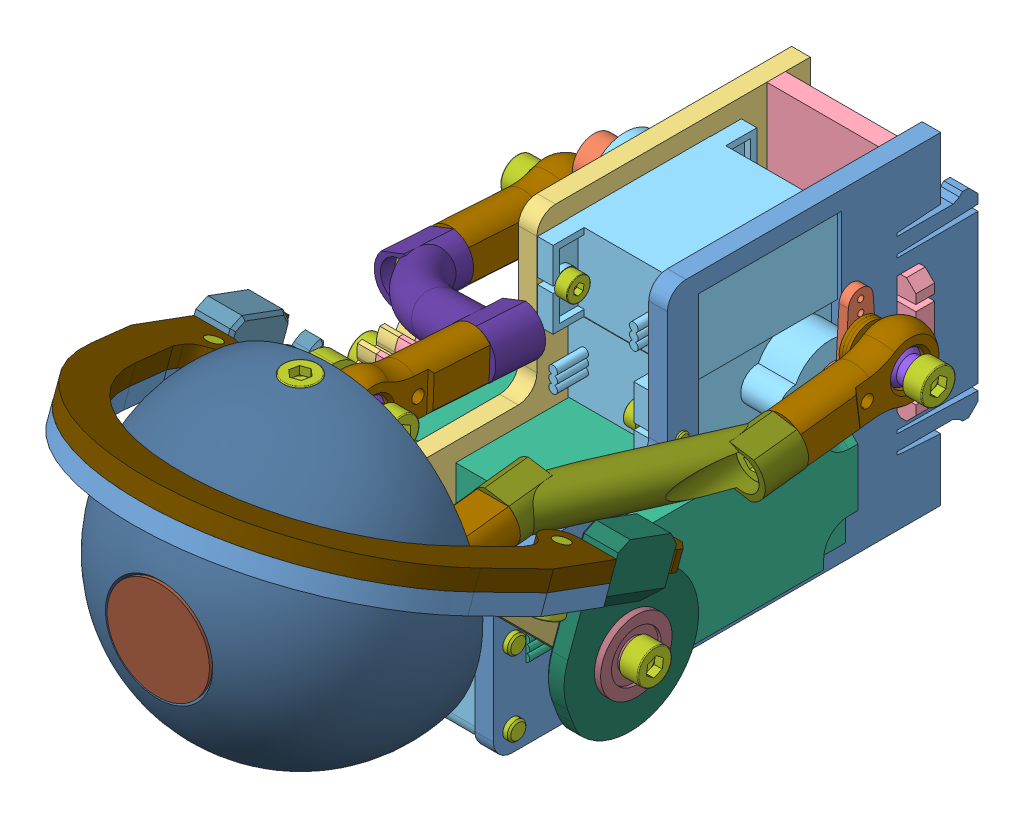
SolidWorks assembly eye, configuration Default. Lengths in mm.
Overall size (70 58.01 124.02).
83 component instances, 27 part files, 174 mates.
Components (placement in the parent):
- eye-frame-2-1: eye-frame-2 [Default] at origin size (3 52 78)
- eye-frame-4-1: eye-frame-4 [Default] at origin size (3 37 29)
- eye-frame-1-1: eye-frame-1 [Default] at origin size (3 52 78)
- eye-frame-3-1: eye-frame-3 [Default] at origin size (30 52 3)
- servo-micro-1: servo-micro [Default] at (11.5 42.75 27.5) x (0 0 1) z (0 -1 0) size (32.8 31.5 12.4)
- servo-micro-2: servo-micro [Default] at (-11.5 30.25 27.5) x (0 0 1) z (0 1 0) size (32.8 31.5 12.4)
- servo-standard-1: servo-standard [Default] at (14.9 13.5 36.5) x (0 0 -1) z (0 1 0) size (58.5 43.2 20.3)
- pivot-beam-1: pivot-beam [Default] at (0 33 91) x (1 0 0) z (0 0.999996 0.002896) size (13.6 17.5 43)
- balljoint-ball-1: balljoint-ball [Default] at (-27 34.2513 22.1498) x (0 -1 0) z (0 0 1) size (6 8 6)
- balljoint-ball-2: balljoint-ball [Default] at (27 38.7499 22.3456) x (0 -0.456904 -0.889516) z (0 0.889516 -0.456904) size (6 8 6)
- balljoint-ball-3: balljoint-ball [Default] at (-0.1 48.0274 81.5435) x (0 -0.381849 0.924225) z (0 -0.924225 -0.381849) size (6 8 6)
- balljoint-housing-1: balljoint-housing [Default] at (27 38.7499 22.3456) x (0.002874 -0.992667 -0.120847) z (-0.003489 -0.120857 0.992664) size (11 6 23.5)
- balljoint-housing-2: balljoint-housing [Default] at (-27 34.2513 22.1498) x (0.013011 -0.998189 0.05873) z (-0.003694 0.058687 0.99827) size (11 6 23.5)
- balljoint-housing-3: balljoint-housing [Default] at (-0.1 48.0274 81.5435) x (-0.020817 0.998056 -0.058751) z (0.003694 -0.058687 -0.99827) size (11 6 23.5)
- eye-shell-1: eye-shell [Default] at (0 33 91) x (0 0.999996 0.002896) z (0.999533 0.000089 -0.03056) size (50 27.56 50)
- iris-1: iris [Default] at (0.7238 32.9314 114.6743) x (-0.245832 0.969257 0.010323) z (-0.968831 -0.246032 0.028909) size (16 3 16)
- balljoint-ball-5: balljoint-ball [Default] at (12.9939 33.0012 90.6027) x (1 0 0) z (0 -0.002896 0.999996) size (6 8 6)
- balljoint-housing-4: balljoint-housing [Default] at (12.9939 33.0012 90.6027) x (-0.999969 -0.006611 -0.00432) z (0.003489 0.120857 -0.992664) size (11 6 23.5)
- eyelid-spacer-1: eyelid-spacer [Default] at (-12 23.5 69) x (0 1 0) z (0 0 1) size (8 16 7)
- eyelid-spacer-2: eyelid-spacer [Default] at (12 23.5 69) x (0 -1 0) z (0 0 1) size (8 16 7)
- bearing-f623-1: bearing-f623 [Default] at (-32 23.5 69) x (0 -1 0) z (0 0 1) size (11.5 4 11.5)
- bearing-f623-2: bearing-f623 [Default] at (32 23.5 69) x (0 -0.381849 0.924225) z (0 -0.924225 -0.381849) size (11.5 4 11.5)
- eyelid-gear-1: eyelid-gear [Default] at (-28 23.5 69) x (0 -0.716341 0.69775) z (-1 0 0) size (27.51 29.21 6)
- eyelid-idler-2: eyelid-idler [Default] at (28 23.5 69) x (0 -0.716341 0.69775) z (-1 0 0) size (25.22 26.99 6)
- lever-horizontal-1: lever-horizontal [Default] at (19.997 35.8755 56.4742) x (0.983361 -0.180711 -0.018545) z (-0.003489 -0.120857 0.992664) size (22 7.47 32.5)
- lever-vertical-1: lever-vertical [Default] at (-13.55 41.1394 51.8466) x (-0.93523 -0.353617 0.017328) z (0.003694 -0.058687 -0.99827) size (37 7.61 24)
- eyelid-2: eyelid [Default] at (0 41.9081 86.4801) x (-1 0 0) z (0 -0.345125 -0.938557) size (68 3 57.5)
- eyelid-lower-1: eyelid-lower [Default] at (0 41.9081 86.4801) x (1 0 0) z (0 -0.345125 -0.938557) size (68 3 44.5)
- servo-horn-micro-1-arm-1: servo-horn-micro-1-arm [Default] at (17 30.25 22.3) x (0 0.999986 0.005367) z (0 0.005367 -0.999986) size (19.5 4.5 7)
- servo-horn-micro-1-arm-2: servo-horn-micro-1-arm [Default] at (-17 42.75 22.3) x (0 -0.999844 -0.01767) z (0 0.01767 -0.999844) size (19.5 4.5 7)
- eyelid-servo-gear-lasered-a-1: eyelid-servo-gear-lasered-a [Default] at (-31.3 13.5 46.6) x (0 0 -1) z (1 0 0) size (26.64 26.59 3)
- eyelid-servo-gear-lasered-b-1: eyelid-servo-gear-lasered-b [Default] at (-28.3 13.5 46.6) x (0 0 -1) z (1 0 0) size (26.64 26.59 3)
- eye-frame-spacer-1: eye-frame-spacer [Default] at (-9 3.5 69) x (0 0 -1) z (0 -1 0) size (9 7.5 27.3)
- eye-frame-spacer-3: eye-frame-spacer [Default] at (9 3.5 69) x (0 0 1) z (0 -1 0) size (9 7.5 27.3)
- pan head cross recess screw_iso-2: pan head cross recess screw_iso [ISO 7045 - M2.5 x 4 - Z --- 4N] at (-22.6 42.75 22.3) size (6.05 5 5)
- socket head cap screw_iso-1: socket head cap screw_iso [ISO 4762 M2 x 6 --- 6N] at (-4.5 42.75 41.75) x (-1 0 0) z (0 -0.924225 -0.381849) size (8 3.8 3.8)
- socket head cap screw_iso-2: socket head cap screw_iso [ISO 4762 M2 x 6 --- 6N] at (-4.5 42.75 13.25) x (-1 0 0) z (0 -0.924225 -0.381849) size (8 3.8 3.8)
- socket head cap screw_iso-3: socket head cap screw_iso [ISO 4762 M2 x 6 --- 6N] at (4.5 30.25 41.75) x (1 0 0) z (0 0.924225 -0.381849) size (8 3.8 3.8)
- socket head cap screw_iso-4: socket head cap screw_iso [ISO 4762 M2 x 6 --- 6N] at (4.5 30.25 13.25) x (1 0 0) z (0 0.924225 -0.381849) size (8 3.8 3.8)
- socket head cap screw_iso-5: socket head cap screw_iso [ISO 4762 M3 x 6 --- 6N] at (-17.5 18.5 61) size (9 5.5 5.5)
- socket head cap screw_iso-6: socket head cap screw_iso [ISO 4762 M3 x 6 --- 6N] at (-17.5 8.5 61) size (9 5.5 5.5)
- socket head cap screw_iso-7: socket head cap screw_iso [ISO 4762 M3 x 6 --- 6N] at (-17.5 18.5 12) size (9 5.5 5.5)
- socket head cap screw_iso-8: socket head cap screw_iso [ISO 4762 M3 x 6 --- 6N] at (-17.5 8.5 12) size (9 5.5 5.5)
- hex nut style 1 gradeab_iso-1: hex nut style 1 gradeab_iso [Hexagon Nut ISO - 4032 - M3 - D - N] at (-3.7 23.5 69) x (0 0 1) z (-1 0 0) size (5.5 6.35 2.4)
- hex nut style 1 gradeab_iso-2: hex nut style 1 gradeab_iso [Hexagon Nut ISO - 4032 - M3 - D - N] at (3.7 23.5 69) x (0 0 1) z (1 0 0) size (5.5 6.35 2.4)
- hex nut style 1 gradeab_iso-3: hex nut style 1 gradeab_iso [Hexagon Nut ISO - 4032 - M3 - D - N] at (-6.4 33 91) x (0 0.86747 -0.49749) z (-1 0 0) size (5.5 6.35 2.4)
- plain washer normal grade a_iso-1: plain washer normal grade a_iso [Washer ISO 7089 - 3] at (-1.8 33 91) size (0.5 7 7)
- plain washer normal grade a_iso-2: plain washer normal grade a_iso [Washer ISO 7089 - 3] at (1.8 33 91) x (-1 0 0) z (0 0.383049 0.923728) size (0.5 7 7)
- plain washer normal grade a_iso-3: plain washer normal grade a_iso [Washer ISO 7089 - 3] at (0 54.9999 91.0637) x (0 0.999996 0.002896) z (0 -0.002896 0.999996) size (0.5 7 7)
- plain washer normal grade a_iso-4: plain washer normal grade a_iso [Washer ISO 7089 - 3] at (0 11.0001 90.9363) x (0 -0.999996 -0.002896) z (0 0.002896 -0.999996) size (0.5 7 7)
- hex nut style 1 gradeab_iso-4: hex nut style 1 gradeab_iso [Hexagon Nut ISO - 4032 - M3 - D - N] at (-8 48.0274 81.5435) x (0 0.999996 0.002896) z (-1 0 0) size (5.5 6.35 2.4)
- hex nut style 1 gradeab_iso-5: hex nut style 1 gradeab_iso [Hexagon Nut ISO - 4032 - M3 - D - N] at (0 19.4001 90.9606) x (-0.5 0.002508 -0.866022) z (0 0.999996 0.002896) size (5.5 6.35 2.4)
- hex nut style 1 gradeab_iso-6: hex nut style 1 gradeab_iso [Hexagon Nut ISO - 4032 - M3 - D - N] at (0 46.5999 91.0394) x (0.5 0.002508 -0.866022) z (0 -0.999996 -0.002896) size (5.5 6.35 2.4)
- socket head cap screw_iso-11: socket head cap screw_iso [ISO 4762 M3 x 10 --- 10N] at (7 33 91) x (-1 0 0) z (0 -0.924225 -0.381849) size (13 5.5 5.5)
- socket head cap screw_iso-12: socket head cap screw_iso [ISO 4762 M3 x 10 --- 10N] at (0 57.9999 91.0724) x (0 -0.999996 -0.002896) z (-0.982583 0.000538 -0.185826) size (13 5.5 5.5)
- socket head cap screw_iso-13: socket head cap screw_iso [ISO 4762 M3 x 10 --- 10N] at (0 8.0001 90.9276) x (0 0.999996 0.002896) z (0.564882 -0.00239 0.825168) size (13 5.5 5.5)
- socket head cap screw_iso-14: socket head cap screw_iso [ISO 4762 M3 x 12 --- 12N] at (6.9 48.0274 81.5435) x (-1 0 0) z (0 -0.853094 -0.521757) size (15 5.5 5.5)
- hex nut style 1 gradeab_iso-7: hex nut style 1 gradeab_iso [Hexagon Nut ISO - 4032 - M3 - D - N] at (12.9939 43.4011 90.6328) x (0.850341 0.001524 -0.52623) z (0 0.999996 0.002896) size (5.5 6.35 2.4)
- socket head cap screw_iso-18: socket head cap screw_iso [ISO 4762 M3 x 16 --- 16N] at (12.9939 26.0012 90.5824) x (0 0.999996 0.002896) z (0 -0.002896 0.999996) size (19 5.5 5.5)
- socket head cap screw_iso-19: socket head cap screw_iso [ISO 4762 M3 x 30 --- 18N] at (-35 23.5 69) size (33 5.5 5.5)
- socket head cap screw_iso-20: socket head cap screw_iso [ISO 4762 M3 x 30 --- 18N] at (35 23.5 69) x (-1 0 0) z (0 -0.924225 -0.381849) size (33 5.5 5.5)
- socket head cap screw_iso-21: socket head cap screw_iso [ISO 4762 M3 x 25 --- 18N] at (-15 15.5 69) size (28 5.5 5.5)
- socket head cap screw_iso-22: socket head cap screw_iso [ISO 4762 M3 x 25 --- 18N] at (-15 3.5 69) size (28 5.5 5.5)
- socket head cap screw_iso-25: socket head cap screw_iso [ISO 4762 M3 x 10 --- 10N] at (13.0742 35.7809 67.7715) x (-0.003489 -0.120857 0.992664) z (-0.992244 0.123762 0.01158) size (13 5.5 5.5)
- socket head cap screw_iso-28: socket head cap screw_iso [ISO 4762 M3 x 10 --- 10N] at (26.9197 35.9702 45.1769) x (0.003489 0.120857 -0.992664) z (0.837028 0.542789 0.069027) size (13 5.5 5.5)
- socket head cap screw_iso-29: socket head cap screw_iso [ISO 4762 M3 x 10 --- 10N] at (-27.0887 35.6598 46.1083) x (0.003694 -0.058687 -0.99827) z (-0.808159 -0.588117 0.031584) size (13 5.5 5.5)
- socket head cap screw_iso-30: socket head cap screw_iso [ISO 4762 M3 x 10 --- 10N] at (-0.0113 46.619 57.585) x (-0.003694 0.058687 0.99827) z (-0.992553 0.121333 -0.010806) size (13 5.5 5.5)
- socket head cap screw_iso-33: socket head cap screw_iso [ISO 4762 M3 x 6 --- 6N] at (-28 33.1706 80.1038) x (0 0.938557 -0.345125) z (0.345125 0.32392 0.880888) size (9 5.5 5.5)
- socket head cap screw_iso-34: socket head cap screw_iso [ISO 4762 M3 x 6 --- 6N] at (28 33.1706 80.1038) x (0 0.938557 -0.345125) z (0.345125 0.32392 0.880888) size (9 5.5 5.5)
- pan head cross recess screw_iso-1: pan head cross recess screw_iso [ISO 7045 - M2.5 x 4 - Z --- 4N] at (22.6 30.25 22.3) x (-1 0 0) z (0 -0.924225 -0.381849) size (6.05 5 5)
- plain washer normal grade a_iso-5: plain washer normal grade a_iso [Washer ISO 7089 - 3] at (22 38.7499 22.3456) size (0.5 7 7)
- plain washer normal grade a_iso-6: plain washer normal grade a_iso [Washer ISO 7089 - 3] at (22.5 38.7499 22.3456) x (1 0 0) z (0 0 -1) size (0.5 7 7)
- plain washer normal grade a_iso-7: plain washer normal grade a_iso [Washer ISO 7089 - 3] at (23 38.7499 22.3456) x (1 0 0) z (0 0 -1) size (0.5 7 7)
- socket head cap screw_iso-38: socket head cap screw_iso [ISO 4762 M3 x 12 --- 12N] at (34 38.7499 22.3456) x (-1 0 0) z (0 -0.924225 -0.381849) size (15 5.5 5.5)
- plain washer normal grade a_iso-8: plain washer normal grade a_iso [Washer ISO 7089 - 3] at (-21.5 34.2513 22.1498) size (0.5 7 7)
- plain washer normal grade a_iso-9: plain washer normal grade a_iso [Washer ISO 7089 - 3] at (-22 34.2513 22.1498) size (0.5 7 7)
- plain washer normal grade a_iso-10: plain washer normal grade a_iso [Washer ISO 7089 - 3] at (-22.5 34.2513 22.1498) size (0.5 7 7)
- socket head cap screw_iso-39: socket head cap screw_iso [ISO 4762 M3 x 12 --- 12N] at (-34 34.2513 22.1498) size (15 5.5 5.5)
- socket head cap screw_iso-40: socket head cap screw_iso [ISO 4762 M3 x 6 --- 6N] at (-34.3 21.5 46.6) x (1 0 0) z (0 0 -1) size (9 5.5 5.5)
- socket head cap screw_iso-41: socket head cap screw_iso [ISO 4762 M3 x 6 --- 6N] at (-34.3 13.5 46.6) x (1 0 0) z (0 0 -1) size (9 5.5 5.5)
- socket head cap screw_iso-42: socket head cap screw_iso [ISO 4762 M3 x 6 --- 6N] at (-34.3 13.5 38.6) x (1 0 0) z (0 0 -1) size (9 5.5 5.5)
- socket head cap screw_iso-43: socket head cap screw_iso [ISO 4762 M3 x 6 --- 6N] at (-34.3 5.5 46.6) x (1 0 0) z (0 0 -1) size (9 5.5 5.5)
- socket head cap screw_iso-44: socket head cap screw_iso [ISO 4762 M3 x 6 --- 6N] at (-34.3 13.5 54.6) x (1 0 0) z (0 0 -1) size (9 5.5 5.5)
Mates (geometry in assembly coordinates):
- Concentric5: concentric aligned: cylinder of eye-frame-1-1 through (-12 42.75 13.25) axis (1 0 0) radius 0.75; cylinder of servo-micro-1 through (-9 42.75 13.25) axis (1 0 0) radius 1
- Concentric6: concentric aligned: cylinder of eye-frame-1-1 through (-12 42.75 41.75) axis (1 0 0) radius 0.75; cylinder of servo-micro-1 through (-9 42.75 41.75) axis (1 0 0) radius 1
- Coincident4: coincident anti-aligned: plane of eye-frame-1-1 through (-9 0 0) normal (1 0 0); plane of servo-micro-1 through (-9 42.75 41.75) normal (-1 0 0)
- Concentric7: concentric aligned: cylinder of servo-micro-1 through (-9 42.75 41.75) axis (1 0 0) radius 1; cylinder of socket head cap screw_iso-1 through (27.25 42.75 41.75) axis (1 0 0) radius 1
- Coincident5: coincident anti-aligned: plane of servo-micro-1 through (-6.5 42.75 41.75) normal (1 0 0); plane of socket head cap screw_iso-1 through (-6.5 43.4755 39.994) normal (-1 0 0)
- Concentric8: concentric aligned: cylinder of servo-micro-1 through (-9 42.75 13.25) axis (1 0 0) radius 1; cylinder of socket head cap screw_iso-2 through (27.25 42.75 13.25) axis (1 0 0) radius 1
- Coincident6: coincident anti-aligned: plane of servo-micro-1 through (-6.5 42.75 13.25) normal (1 0 0); plane of socket head cap screw_iso-2 through (-6.5 43.4755 11.494) normal (-1 0 0)
- Concentric9: concentric aligned: cylinder of socket head cap screw_iso-3 through (-27.25 30.25 41.75) axis (-1 0 0) radius 1; cylinder of servo-micro-2 through (9 30.25 41.75) axis (-1 0 0) radius 1
- Coincident7: coincident anti-aligned: plane of socket head cap screw_iso-3 through (6.5 29.5245 39.994) normal (1 0 0); plane of servo-micro-2 through (6.5 30.25 41.75) normal (-1 0 0)
- Concentric10: concentric aligned: cylinder of socket head cap screw_iso-4 through (-27.25 30.25 13.25) axis (-1 0 0) radius 1; cylinder of servo-micro-2 through (9 30.25 13.25) axis (-1 0 0) radius 1
- Coincident8: coincident anti-aligned: plane of socket head cap screw_iso-4 through (6.5 29.5245 11.494) normal (1 0 0); plane of servo-micro-2 through (6.5 30.25 13.25) normal (-1 0 0)
- Concentric11: concentric aligned: cylinder of eye-frame-2-1 through (12 30.25 13.25) axis (-1 0 0) radius 0.75; cylinder of servo-micro-2 through (9 30.25 13.25) axis (-1 0 0) radius 1
- Concentric12: concentric aligned: cylinder of eye-frame-2-1 through (12 30.25 41.75) axis (-1 0 0) radius 0.75; cylinder of servo-micro-2 through (9 30.25 41.75) axis (-1 0 0) radius 1
- Coincident9: coincident anti-aligned: plane of eye-frame-2-1 through (9 0 0) normal (-1 0 0); plane of servo-micro-2 through (9 30.25 41.75) normal (1 0 0)
- Concentric13: concentric: cylinder of eye-frame-1-1 through (-12 18.5 61) axis (1 0 0) radius 1.25; point of servo-standard-1
- Concentric14: concentric: cylinder of eye-frame-1-1 through (-12 8.5 12) axis (1 0 0) radius 1.25; point of servo-standard-1
- Coincident13: coincident anti-aligned: plane of eye-frame-1-1 through (-12 0 0) normal (-1 0 0); plane of servo-standard-1 through (-12 13.5 36.5) normal (1 0 0)
- Concentric15: concentric anti-aligned: cylinder of eye-frame-1-1 through (-12 18.5 61) axis (1 0 0) radius 1.25; cylinder of socket head cap screw_iso-5 through (-49.25 18.5 61) axis (-1 0 0) radius 1.5
- Coincident14: coincident anti-aligned: plane of servo-standard-1 through (-14.5 13.5 36.5) normal (-1 0 0); plane of socket head cap screw_iso-5 through (-14.5 21.25 61) normal (1 0 0)
- Concentric16: concentric anti-aligned: cylinder of eye-frame-1-1 through (-12 8.5 61) axis (1 0 0) radius 1.25; cylinder of socket head cap screw_iso-6 through (-49.25 8.5 61) axis (-1 0 0) radius 1.5
- Coincident15: coincident anti-aligned: plane of servo-standard-1 through (-14.5 13.5 36.5) normal (-1 0 0); plane of socket head cap screw_iso-6 through (-14.5 11.25 61) normal (1 0 0)
- Concentric17: concentric anti-aligned: cylinder of eye-frame-1-1 through (-12 18.5 12) axis (1 0 0) radius 1.25; cylinder of socket head cap screw_iso-7 through (-49.25 18.5 12) axis (-1 0 0) radius 1.5
- Coincident16: coincident anti-aligned: plane of servo-standard-1 through (-14.5 13.5 36.5) normal (-1 0 0); plane of socket head cap screw_iso-7 through (-14.5 21.25 12) normal (1 0 0)
- Concentric18: concentric anti-aligned: cylinder of eye-frame-1-1 through (-12 8.5 12) axis (1 0 0) radius 1.25; cylinder of socket head cap screw_iso-8 through (-49.25 8.5 12) axis (-1 0 0) radius 1.5
- Coincident17: coincident anti-aligned: plane of servo-standard-1 through (-14.5 13.5 36.5) normal (-1 0 0); plane of socket head cap screw_iso-8 through (-14.5 11.25 12) normal (1 0 0)
- Concentric26: concentric anti-aligned: cylinder of pivot-beam-1 through (-6 33 91) axis (1 0 0) radius 1.6; cylinder of hex nut style 1 gradeab_iso-3 through (-4 33 91) axis (-1 0 0) radius 1.25
- Parallel3: parallel anti-aligned: plane of pivot-beam-1 through (-4 31.3753 93.7953) normal (0 0.002896 -0.999996); plane of hex nut style 1 gradeab_iso-3 through (-4 31.4043 93.7454) normal (0 -0.002896 0.999996)
- Coincident26: coincident anti-aligned: plane of pivot-beam-1 through (-4 33 91) normal (-1 0 0); plane of hex nut style 1 gradeab_iso-3 through (-4 31.4203 88.2454) normal (1 0 0)
- Concentric27: concentric anti-aligned: cylinder of pivot-beam-1 through (-6 33 91) axis (1 0 0) radius 1.6; cylinder of plain washer normal grade a_iso-1 through (-36.725 33 91) axis (-1 0 0) radius 1.6
- Coincident27: coincident anti-aligned: plane of pivot-beam-1 through (-2.3 23.9899 94.4739) normal (1 0 0); plane of plain washer normal grade a_iso-1 through (-2.3 36.5 91) normal (-1 0 0)
- Concentric28: concentric aligned: cylinder of pivot-beam-1 through (-6 33 91) axis (1 0 0) radius 1.6; cylinder of plain washer normal grade a_iso-2 through (36.725 33 91) axis (1 0 0) radius 1.6
- Coincident28: coincident anti-aligned: plane of pivot-beam-1 through (2.3 23.9899 94.4739) normal (-1 0 0); plane of plain washer normal grade a_iso-2 through (2.3 29.767 92.3407) normal (1 0 0)
- Concentric29: concentric anti-aligned: cylinder of pivot-beam-1 through (0 38.5 91.0159) axis (0 0.999996 0.002896) radius 1.6; cylinder of plain washer normal grade a_iso-3 through (0 20.0751 90.9626) axis (0 -0.999996 -0.002896) radius 1.6
- Coincident29: coincident anti-aligned: plane of pivot-beam-1 through (0 54.4999 91.0623) normal (0 0.999996 0.002896); plane of plain washer normal grade a_iso-3 through (-3.5 54.4999 91.0623) normal (0 -0.999996 -0.002896)
- Concentric30: concentric anti-aligned: cylinder of pivot-beam-1 through (0 27.5 90.9841) axis (0 -0.999996 -0.002896) radius 1.6; cylinder of plain washer normal grade a_iso-4 through (0 45.9249 91.0374) axis (0 0.999996 0.002896) radius 1.6
- Coincident30: coincident anti-aligned: plane of pivot-beam-1 through (0 11.5001 90.9377) normal (0 -0.999996 -0.002896); plane of plain washer normal grade a_iso-4 through (-3.5 11.5001 90.9377) normal (0 0.999996 0.002896)
- Concentric31: concentric anti-aligned: cylinder of pivot-beam-1 through (-7.6 48.0274 81.5435) axis (1 0 0) radius 1.6; cylinder of hex nut style 1 gradeab_iso-4 through (-5.6 48.0274 81.5435) axis (-1 0 0) radius 1.25
- Parallel4: parallel anti-aligned: plane of pivot-beam-1 through (-5.6 45.1226 83.2094) normal (0 0.502506 -0.864574); plane of hex nut style 1 gradeab_iso-4 through (-5.6 45.2729 83.1232) normal (0 -0.502506 0.864574)
- Coincident31: coincident anti-aligned: plane of pivot-beam-1 through (-5.6 33 91) normal (-1 0 0); plane of hex nut style 1 gradeab_iso-4 through (-5.6 48.0366 78.3681) normal (1 0 0)
- Concentric32: concentric anti-aligned: cylinder of pivot-beam-1 through (0 27.5 90.9841) axis (0 -0.999996 -0.002896) radius 1.6; cylinder of hex nut style 1 gradeab_iso-5 through (0 17.0001 90.9537) axis (0 0.999996 0.002896) radius 1.25
- Parallel5: parallel anti-aligned: plane of pivot-beam-1 through (2.9 17.0406 76.9537) normal (-1 0 0); plane of hex nut style 1 gradeab_iso-5 through (2.75 16.9955 92.5414) normal (1 0 0)
- Coincident32: coincident anti-aligned: plane of pivot-beam-1 through (-2.9 17.0406 76.9537) normal (0 0.999996 0.002896); plane of hex nut style 1 gradeab_iso-5 through (-2.75 16.9955 92.5414) normal (0 -0.999996 -0.002896)
- Concentric33: concentric anti-aligned: cylinder of pivot-beam-1 through (0 38.5 91.0159) axis (0 0.999996 0.002896) radius 1.6; cylinder of hex nut style 1 gradeab_iso-6 through (0 48.9999 91.0463) axis (0 -0.999996 -0.002896) radius 1.25
- Parallel6: parallel anti-aligned: plane of pivot-beam-1 through (-2.9 49.0405 77.0464) normal (1 0 0); plane of hex nut style 1 gradeab_iso-6 through (-2.75 48.9953 92.634) normal (-1 0 0)
- Coincident33: coincident anti-aligned: plane of pivot-beam-1 through (-2.9 49.0405 77.0464) normal (0 -0.999996 -0.002896); plane of hex nut style 1 gradeab_iso-6 through (2.75 48.9953 92.634) normal (0 0.999996 0.002896)
- Concentric34: concentric anti-aligned: cylinder of eye-frame-4-1 through (1.5 33 91) axis (-1 0 0) radius 1.5; cylinder of pivot-beam-1 through (-6 33 91) axis (1 0 0) radius 1.6
- Width1: width aligned: plane of pivot-beam-1 through (2.3 23.9899 94.4739) normal (-1 0 0); plane of pivot-beam-1 through (-2.3 23.9899 94.4739) normal (1 0 0); plane of eye-frame-4-1 through (-1.5 33 91) normal (-1 0 0); plane of eye-frame-4-1 through (1.5 33 91) normal (1 0 0)
- Concentric35: concentric aligned: cylinder of pivot-beam-1 through (-6 33 91) axis (1 0 0) radius 1.6; cylinder of socket head cap screw_iso-11 through (38.75 33 91) axis (1 0 0) radius 1.5
- Coincident34: coincident anti-aligned: plane of pivot-beam-1 through (4 33 91) normal (1 0 0); plane of socket head cap screw_iso-11 through (4 34.0501 88.4584) normal (-1 0 0)
- Concentric36: concentric anti-aligned: cylinder of plain washer normal grade a_iso-3 through (0 20.0751 90.9626) axis (0 -0.999996 -0.002896) radius 1.6; cylinder of socket head cap screw_iso-12 through (0 89.7498 91.1644) axis (0 0.999996 0.002896) radius 1.5
- Coincident35: coincident anti-aligned: plane of plain washer normal grade a_iso-3 through (-1.6 54.9999 91.0637) normal (0 0.999996 0.002896); plane of socket head cap screw_iso-12 through (-0.511 54.9921 93.7658) normal (0 -0.999996 -0.002896)
- Concentric37: concentric anti-aligned: cylinder of plain washer normal grade a_iso-4 through (0 45.9249 91.0374) axis (0 0.999996 0.002896) radius 1.6; cylinder of socket head cap screw_iso-13 through (0 -23.7498 90.8356) axis (0 -0.999996 -0.002896) radius 1.5
- Coincident36: coincident anti-aligned: plane of plain washer normal grade a_iso-4 through (-1.6 11.0001 90.9363) normal (0 -0.999996 -0.002896); plane of socket head cap screw_iso-13 through (-2.2692 10.9956 92.4897) normal (0 0.999996 0.002896)
- Concentric40: concentric anti-aligned: cylinder of pivot-beam-1 through (-7.6 48.0274 81.5435) axis (1 0 0) radius 1.6; cylinder of balljoint-ball-3 through (-11.0319 48.0274 81.5435) axis (-1 0 0) radius 1.5
- Coincident39: coincident anti-aligned: plane of pivot-beam-1 through (-4.1 48.0274 81.5435) normal (1 0 0); plane of balljoint-ball-3 through (-4.1 47.4547 82.9298) normal (-1 0 0)
- Concentric41: concentric anti-aligned: cylinder of balljoint-ball-3 through (-11.0319 48.0274 81.5435) axis (-1 0 0) radius 1.5; cylinder of socket head cap screw_iso-14 through (38.65 48.0274 81.5435) axis (1 0 0) radius 1.5
- Coincident40: coincident anti-aligned: plane of balljoint-ball-3 through (3.9 47.2638 83.3919) normal (1 0 0); plane of socket head cap screw_iso-14 through (3.9 49.4623 79.1975) normal (-1 0 0)
- Concentric44: concentric: sphere of balljoint-ball-2; sphere of balljoint-housing-1
- Concentric45: concentric: sphere of balljoint-ball-1; sphere of balljoint-housing-2
- Concentric46: concentric: sphere of balljoint-ball-3; sphere of balljoint-housing-3
- Concentric47: concentric anti-aligned: cylinder of socket head cap screw_iso-12 through (0 89.7498 91.1644) axis (0 0.999996 0.002896) radius 2.75; cylinder of eye-shell-1 through (0 57.9999 91.0724) axis (0 -0.999996 -0.002896) radius 2.75
- Width2: width anti-aligned: plane of eye-shell-1 through (0 54.9999 91.0637) normal (0 -0.999996 -0.002896); plane of eye-shell-1 through (0 11.0001 90.9363) normal (0 0.999996 0.002896); plane of plain washer normal grade a_iso-3 through (-1.6 54.9999 91.0637) normal (0 0.999996 0.002896); plane of plain washer normal grade a_iso-4 through (-1.6 11.0001 90.9363) normal (0 -0.999996 -0.002896)
- Concentric48: concentric anti-aligned: cylinder of eye-shell-1 through (0 33 91) axis (-0.03056 0.002895 -0.999529) radius 8; cylinder of iris-1 through (0.6322 32.9401 111.6757) axis (0.03056 -0.002895 0.999529) radius 8
- Coincident43: coincident anti-aligned: plane of eye-shell-1 through (0.6322 32.9401 111.6757) normal (0.03056 -0.002895 0.999529); plane of iris-1 through (0.6322 32.9401 111.6757) normal (-0.03056 0.002895 -0.999529)
- Concentric49: concentric anti-aligned: cylinder of eye-shell-1 through (12.9939 500030.9044 1538.6206) axis (0 -0.999996 -0.002896) radius 1.6; cylinder of hex nut style 1 gradeab_iso-7 through (12.9939 41.0011 90.6259) axis (0 0.999996 0.002896) radius 1.25
- Parallel7: parallel anti-aligned: plane of eye-shell-1 through (9.0875 40.9921 93.7467) normal (-0.03056 0.002895 -0.999529); plane of hex nut style 1 gradeab_iso-7 through (11.491 40.993 93.4231) normal (0.03056 -0.002895 0.999529)
- Coincident44: coincident anti-aligned: plane of eye-shell-1 through (0 41 91.0232) normal (0 0.999996 0.002896); plane of hex nut style 1 gradeab_iso-7 through (11.3229 41.0089 87.9257) normal (0 -0.999996 -0.002896)
- Coincident47: coincident anti-aligned: plane of eye-shell-1 through (12.9939 37.0011 90.6143) normal (0 -0.999996 -0.002896); plane of balljoint-ball-5 through (14.4939 37.0011 90.6143) normal (0 0.999996 0.002896)
- Concentric53: concentric anti-aligned: cylinder of eye-shell-1 through (12.9939 500030.9044 1538.6206) axis (0 -0.999996 -0.002896) radius 1.6; cylinder of balljoint-ball-5 through (12.9939 43.933 90.6344) axis (0 0.999996 0.002896) radius 1.5
- Concentric54: concentric anti-aligned: cylinder of balljoint-ball-5 through (12.9939 43.933 90.6344) axis (0 0.999996 0.002896) radius 1.5; cylinder of socket head cap screw_iso-18 through (12.9939 -5.7487 90.4905) axis (0 -0.999996 -0.002896) radius 1.5
- Coincident48: coincident anti-aligned: plane of balljoint-ball-5 through (14.9939 29.0012 90.5911) normal (0 -0.999996 -0.002896); plane of socket head cap screw_iso-18 through (10.2439 29.0012 90.5911) normal (0 0.999996 0.002896)
- Concentric55: concentric: sphere of balljoint-ball-5; sphere of balljoint-housing-4
- Concentric56: concentric aligned: cylinder of eye-frame-1-1 through (-12 23.5 69) axis (1 0 0) radius 1.5; cylinder of eyelid-spacer-1 through (-27 23.5 69) axis (1 0 0) radius 1.6
- Coincident49: coincident anti-aligned: plane of eye-frame-1-1 through (-12 0 0) normal (-1 0 0); plane of eyelid-spacer-1 through (-12 23.5 69) normal (1 0 0)
- Parallel8: parallel aligned: plane of eye-frame-1-1 through (-12 0 72) normal (0 0 1); plane of eyelid-spacer-1 through (-27 21.5635 72.5) normal (0 0 1)
- Concentric57: concentric aligned: cylinder of eye-frame-2-1 through (12 23.5 69) axis (-1 0 0) radius 1.5; cylinder of eyelid-spacer-2 through (27 23.5 69) axis (-1 0 0) radius 1.6
- Coincident51: coincident anti-aligned: plane of eye-frame-2-1 through (12 0 0) normal (1 0 0); plane of eyelid-spacer-2 through (12 23.5 69) normal (-1 0 0)
- Parallel9: parallel aligned: plane of eye-frame-2-1 through (12 0 72) normal (0 0 1); plane of eyelid-spacer-2 through (27 25.4365 72.5) normal (0 0 1)
- Concentric58: concentric anti-aligned: cylinder of eyelid-spacer-1 through (-27 23.5 69) axis (1 0 0) radius 1.6; cylinder of bearing-f623-1 through (-52.7975 23.5 69) axis (-1 0 0) radius 1.5
- Coincident52: coincident anti-aligned: plane of eyelid-spacer-1 through (-28 23.5 69) normal (-1 0 0); plane of bearing-f623-1 through (-28 19.5 69) normal (1 0 0)
- Concentric59: concentric anti-aligned: cylinder of eyelid-spacer-2 through (27 23.5 69) axis (-1 0 0) radius 1.6; cylinder of bearing-f623-2 through (52.7975 23.5 69) axis (1 0 0) radius 1.5
- Coincident53: coincident anti-aligned: plane of eyelid-spacer-2 through (28 23.5 69) normal (1 0 0); plane of bearing-f623-2 through (28 21.9726 72.6969) normal (-1 0 0)
- Concentric60: concentric aligned: cylinder of bearing-f623-1 through (-52.7975 23.5 69) axis (-1 0 0) radius 1.5; cylinder of socket head cap screw_iso-19 through (-66.75 23.5 69) axis (-1 0 0) radius 1.5
- Coincident54: coincident anti-aligned: plane of bearing-f623-1 through (-32 21 69) normal (-1 0 0); plane of socket head cap screw_iso-19 through (-32 26.25 69) normal (1 0 0)
- Concentric61: concentric aligned: cylinder of bearing-f623-2 through (52.7975 23.5 69) axis (1 0 0) radius 1.5; cylinder of socket head cap screw_iso-20 through (66.75 23.5 69) axis (1 0 0) radius 1.5
- Coincident55: coincident anti-aligned: plane of bearing-f623-2 through (32 22.5454 71.3106) normal (1 0 0); plane of socket head cap screw_iso-20 through (32 24.5501 66.4584) normal (-1 0 0)
- Concentric62: concentric anti-aligned: cylinder of eye-frame-1-1 through (-12 15.5 69) axis (1 0 0) radius 1.5; cylinder of socket head cap screw_iso-21 through (-46.75 15.5 69) axis (-1 0 0) radius 1.5
- Coincident56: coincident anti-aligned: plane of eye-frame-1-1 through (-12 0 0) normal (-1 0 0); plane of socket head cap screw_iso-21 through (-12 18.25 69) normal (1 0 0)
- Concentric63: concentric anti-aligned: cylinder of eye-frame-1-1 through (-12 3.5 69) axis (1 0 0) radius 1.5; cylinder of socket head cap screw_iso-22 through (-46.75 3.5 69) axis (-1 0 0) radius 1.5
- Coincident57: coincident anti-aligned: plane of eye-frame-1-1 through (-12 0 0) normal (-1 0 0); plane of socket head cap screw_iso-22 through (-12 6.25 69) normal (1 0 0)
- Concentric66: concentric anti-aligned: cylinder of bearing-f623-1 through (-52.7975 23.5 69) axis (-1 0 0) radius 5; cylinder of eyelid-gear-1 through (-34 23.5 69) axis (1 0 0) radius 5
- Coincident59: coincident anti-aligned: plane of bearing-f623-1 through (-31 18.5 69) normal (1 0 0); plane of eyelid-gear-1 through (-31 23.5 69) normal (-1 0 0)
- Concentric68: concentric anti-aligned: cylinder of bearing-f623-2 through (52.7975 23.5 69) axis (1 0 0) radius 5; cylinder of eyelid-idler-2 through (34 23.5 69) axis (-1 0 0) radius 5
- Coincident61: coincident anti-aligned: plane of bearing-f623-2 through (31 21.5908 73.6211) normal (-1 0 0); plane of eyelid-idler-2 through (31 23.5 69) normal (1 0 0)
- Concentric73: concentric aligned: cylinder of balljoint-housing-1 through (26.9372 36.5745 40.2136) axis (-0.003489 -0.120857 0.992664) radius 1.25; cylinder of lever-horizontal-1 through (26.9372 36.5745 40.2136) axis (-0.003489 -0.120857 0.992664) radius 1.6
- Coincident70: coincident anti-aligned: plane of balljoint-housing-1 through (29.93 39.0634 40.5271) normal (-0.003489 -0.120857 0.992664); plane of lever-horizontal-1 through (26.9372 36.5745 40.2136) normal (0.003489 0.120857 -0.992664)
- Concentric74: concentric anti-aligned: cylinder of balljoint-housing-4 through (13.0567 35.1766 72.7348) axis (0.003489 0.120857 -0.992664) radius 1.25; cylinder of lever-horizontal-1 through (13.0812 36.0226 65.7861) axis (-0.003489 -0.120857 0.992664) radius 4
- Coincident73: coincident anti-aligned: plane of balljoint-housing-4 through (15.5354 38.171 73.1081) normal (0.003489 0.120857 -0.992664); plane of lever-horizontal-1 through (13.0567 35.1766 72.7348) normal (-0.003489 -0.120857 0.992664)
- Concentric75: concentric aligned: cylinder of balljoint-housing-2 through (-27.0665 35.3077 40.1187) axis (-0.003694 0.058687 0.99827) radius 1.25; cylinder of lever-vertical-1 through (-27.0665 35.3077 40.1187) axis (-0.003694 0.058687 0.99827) radius 1.6
- Concentric76: concentric aligned: cylinder of balljoint-housing-3 through (-0.0335 46.9711 63.5746) axis (0.003694 -0.058687 -0.99827) radius 1.25; cylinder of lever-vertical-1 through (-0.0335 46.9711 63.5746) axis (0.003694 -0.058687 -0.99827) radius 1.6
- Coincident74: coincident anti-aligned: plane of balljoint-housing-3 through (3.0179 44.5389 63.7289) normal (0.003694 -0.058687 -0.99827); plane of lever-vertical-1 through (-0.0335 46.9711 63.5746) normal (-0.003694 0.058687 0.99827)
- Coincident75: coincident anti-aligned: plane of balljoint-housing-2 through (-24.0993 37.8428 39.9806) normal (-0.003694 0.058687 0.99827); plane of lever-vertical-1 through (-27.0665 35.3077 40.1187) normal (0.003694 -0.058687 -0.99827)
- Coincident76: coincident anti-aligned: plane of lever-horizontal-1 through (13.0637 35.4183 70.7494) normal (0.003489 0.120857 -0.992664); plane of socket head cap screw_iso-25 through (13.4054 38.1268 71.0804) normal (-0.003489 -0.120857 0.992664)
- Concentric78: concentric aligned: cylinder of lever-horizontal-1 through (13.0567 35.1766 72.7348) axis (0.003489 0.120857 -0.992664) radius 1.6; cylinder of socket head cap screw_iso-25 through (13.185 39.6181 36.2544) axis (0.003489 0.120857 -0.992664) radius 1.5
- Coincident77: coincident anti-aligned: plane of lever-horizontal-1 through (26.9302 36.3327 42.1989) normal (-0.003489 -0.120857 0.992664); plane of socket head cap screw_iso-28 through (25.4256 38.6183 42.4719) normal (0.003489 0.120857 -0.992664)
- Concentric79: concentric aligned: cylinder of lever-horizontal-1 through (26.9372 36.5745 40.2136) axis (-0.003489 -0.120857 0.992664) radius 1.6; cylinder of socket head cap screw_iso-28 through (26.809 32.133 76.694) axis (-0.003489 -0.120857 0.992664) radius 1.5
- Coincident78: coincident anti-aligned: plane of lever-vertical-1 through (-27.0776 35.4838 43.1135) normal (-0.003694 0.058687 0.99827); plane of socket head cap screw_iso-29 through (-25.458 33.2655 43.2499) normal (0.003694 -0.058687 -0.99827)
- Concentric80: concentric aligned: cylinder of lever-vertical-1 through (-27.0665 35.3077 40.1187) axis (-0.003694 0.058687 0.99827) radius 1.6; cylinder of socket head cap screw_iso-29 through (-27.206 37.5231 77.8033) axis (-0.003694 0.058687 0.99827) radius 1.5
- Coincident79: coincident anti-aligned: plane of lever-vertical-1 through (-0.0224 46.795 60.5798) normal (0.003694 -0.058687 -0.99827); plane of socket head cap screw_iso-30 through (0.3124 49.5199 60.4209) normal (-0.003694 0.058687 0.99827)
- Concentric81: concentric aligned: cylinder of lever-vertical-1 through (-0.0335 46.9711 63.5746) axis (0.003694 -0.058687 -0.99827) radius 1.6; cylinder of socket head cap screw_iso-30 through (0.106 44.7556 25.89) axis (0.003694 -0.058687 -0.99827) radius 1.5
- Coincident89: coincident aligned: plane of eyelid-gear-1 through (-64.6177 39.2897 64.0027) normal (0 0.938557 -0.345125); plane of eyelid-idler-2 through (64.6177 39.2897 64.0027) normal (0 0.938557 -0.345125)
- Coincident90: coincident anti-aligned: plane of eyelid-gear-1 through (-33 30.6098 47.0623) normal (0 -0.938557 0.345125); plane of eyelid-2 through (0 44.7238 85.4447) normal (0 0.938557 -0.345125)
- Width3: width anti-aligned: plane of eyelid-gear-1 through (-33 30.6098 47.0623) normal (1 0 0); plane of eyelid-idler-2 through (33 30.6098 47.0623) normal (-1 0 0); plane of eyelid-2 through (-32.9 37.4761 65.735) normal (-1 0 0); plane of eyelid-2 through (32.9 37.4761 65.735) normal (1 0 0)
- Coincident91: coincident anti-aligned: plane of eyelid-gear-1 through (-64.6177 42.7409 73.3882) normal (0 0.345125 0.938557); plane of eyelid-2 through (-32.9 40.5823 74.182) normal (0 -0.345125 -0.938557)
- Coincident92: coincident anti-aligned: plane of eyelid-2 through (0 41.9081 86.4801) normal (0 -0.938557 0.345125); plane of eyelid-lower-1 through (0 41.9081 86.4801) normal (0 0.938557 -0.345125)
- Concentric90: concentric aligned: cylinder of eyelid-2 through (-28 38.802 78.0331) axis (0 0.938557 -0.345125) radius 1.25; cylinder of eyelid-lower-1 through (-28 35.9863 79.0685) axis (0 0.938557 -0.345125) radius 1.5
- Concentric91: concentric aligned: cylinder of eyelid-2 through (28 38.802 78.0331) axis (0 0.938557 -0.345125) radius 1.25; cylinder of eyelid-lower-1 through (28 35.9863 79.0685) axis (0 0.938557 -0.345125) radius 1.5
- Concentric92: concentric anti-aligned: cylinder of eyelid-lower-1 through (-28 35.9863 79.0685) axis (0 0.938557 -0.345125) radius 1.5; cylinder of socket head cap screw_iso-33 through (-28 3.3715 91.0616) axis (0 -0.938557 0.345125) radius 1.5
- Coincident93: coincident anti-aligned: plane of eyelid-lower-1 through (0 39.0924 87.5155) normal (0 -0.938557 0.345125); plane of socket head cap screw_iso-33 through (-30.581 36.3139 79.9592) normal (0 0.938557 -0.345125)
- Concentric93: concentric anti-aligned: cylinder of eyelid-lower-1 through (28 35.9863 79.0685) axis (0 0.938557 -0.345125) radius 1.5; cylinder of socket head cap screw_iso-34 through (28 3.3715 91.0616) axis (0 -0.938557 0.345125) radius 1.5
- Coincident94: coincident anti-aligned: plane of eyelid-lower-1 through (0 39.0924 87.5155) normal (0 -0.938557 0.345125); plane of socket head cap screw_iso-34 through (25.419 36.3139 79.9592) normal (0 0.938557 -0.345125)
- Concentric96: concentric aligned: cylinder of servo-micro-2 through (20 30.25 22.3) axis (-1 0 0) radius 2.5; cylinder of servo-horn-micro-1-arm-1 through (20 30.25 22.3) axis (-1 0 0) radius 2.5
- Coincident97: coincident anti-aligned: plane of servo-micro-2 through (20 30.25 22.3) normal (1 0 0); plane of servo-horn-micro-1-arm-1 through (20 30.25 22.3) normal (-1 0 0)
- Coincident99: coincident anti-aligned: plane of servo-horn-micro-1-arm-1 through (20.5 30.25 22.3) normal (1 0 0); plane of pan head cross recess screw_iso-1 through (20.5 30.7273 21.1447) normal (-1 0 0)
- Concentric98: concentric aligned: cylinder of servo-horn-micro-1-arm-1 through (17 30.25 22.3) axis (1 0 0) radius 1.25; cylinder of pan head cross recess screw_iso-1 through (48 30.25 22.3) axis (1 0 0) radius 1.25
- Concentric99: concentric anti-aligned: cylinder of servo-horn-micro-1-arm-1 through (17 38.7499 22.3456) axis (1 0 0) radius 0.5; cylinder of plain washer normal grade a_iso-5 through (-12.925 38.7499 22.3456) axis (-1 0 0) radius 1.6
- Coincident100: coincident anti-aligned: plane of servo-horn-micro-1-arm-1 through (21.5 30.25 22.3) normal (1 0 0); plane of plain washer normal grade a_iso-5 through (21.5 42.2499 22.3456) normal (-1 0 0)
- Concentric100: concentric aligned: cylinder of plain washer normal grade a_iso-5 through (-12.925 38.7499 22.3456) axis (-1 0 0) radius 1.6; cylinder of plain washer normal grade a_iso-6 through (-12.425 38.7499 22.3456) axis (-1 0 0) radius 1.6
- Coincident101: coincident anti-aligned: plane of plain washer normal grade a_iso-5 through (22 40.3499 22.3456) normal (1 0 0); plane of plain washer normal grade a_iso-6 through (22 35.2499 22.3456) normal (-1 0 0)
- Concentric101: concentric aligned: cylinder of plain washer normal grade a_iso-6 through (-12.425 38.7499 22.3456) axis (-1 0 0) radius 1.6; cylinder of plain washer normal grade a_iso-7 through (-11.925 38.7499 22.3456) axis (-1 0 0) radius 1.6
- Coincident102: coincident anti-aligned: plane of plain washer normal grade a_iso-6 through (22.5 37.1499 22.3456) normal (1 0 0); plane of plain washer normal grade a_iso-7 through (22.5 35.2499 22.3456) normal (-1 0 0)
- Coincident103: coincident anti-aligned: plane of balljoint-ball-2 through (23 38.0645 21.0113) normal (-1 0 0); plane of plain washer normal grade a_iso-7 through (23 37.1499 22.3456) normal (1 0 0)
- Concentric102: concentric aligned: cylinder of balljoint-ball-2 through (16.0681 38.7499 22.3456) axis (-1 0 0) radius 1.5; cylinder of plain washer normal grade a_iso-7 through (-11.925 38.7499 22.3456) axis (-1 0 0) radius 1.6
- Coincident104: coincident anti-aligned: plane of balljoint-ball-2 through (31 37.8361 20.5666) normal (1 0 0); plane of socket head cap screw_iso-38 through (31 39.8 19.804) normal (-1 0 0)
- Concentric103: concentric anti-aligned: cylinder of balljoint-ball-2 through (16.0681 38.7499 22.3456) axis (-1 0 0) radius 1.5; cylinder of socket head cap screw_iso-38 through (65.75 38.7499 22.3456) axis (1 0 0) radius 1.5
- Concentric104: concentric aligned: cylinder of servo-micro-1 through (-20 42.75 22.3) axis (1 0 0) radius 2.5; cylinder of servo-horn-micro-1-arm-2 through (-20 42.75 22.3) axis (1 0 0) radius 2.5
- Coincident105: coincident anti-aligned: plane of servo-micro-1 through (-20 42.75 22.3) normal (-1 0 0); plane of servo-horn-micro-1-arm-2 through (-20 42.75 22.3) normal (1 0 0)
- Coincident106: coincident anti-aligned: plane of servo-horn-micro-1-arm-2 through (-20.5 42.75 22.3) normal (-1 0 0); plane of pan head cross recess screw_iso-2 through (-20.5 44 22.3) normal (1 0 0)
- Concentric105: concentric aligned: cylinder of servo-horn-micro-1-arm-2 through (-17 42.75 22.3) axis (-1 0 0) radius 1.25; cylinder of pan head cross recess screw_iso-2 through (-48 42.75 22.3) axis (-1 0 0) radius 1.25
- Concentric106: concentric aligned: cylinder of servo-horn-micro-1-arm-2 through (-17 34.2513 22.1498) axis (-1 0 0) radius 0.5; cylinder of plain washer normal grade a_iso-8 through (-56.425 34.2513 22.1498) axis (-1 0 0) radius 1.6
- Coincident107: coincident anti-aligned: plane of servo-horn-micro-1-arm-2 through (-21.5 42.75 22.3) normal (-1 0 0); plane of plain washer normal grade a_iso-8 through (-21.5 35.8513 22.1498) normal (1 0 0)
- Concentric107: concentric aligned: cylinder of plain washer normal grade a_iso-8 through (-56.425 34.2513 22.1498) axis (-1 0 0) radius 1.6; cylinder of plain washer normal grade a_iso-9 through (-56.925 34.2513 22.1498) axis (-1 0 0) radius 1.6
- Coincident108: coincident anti-aligned: plane of plain washer normal grade a_iso-8 through (-22 37.7513 22.1498) normal (-1 0 0); plane of plain washer normal grade a_iso-9 through (-22 35.8513 22.1498) normal (1 0 0)
- Concentric108: concentric aligned: cylinder of plain washer normal grade a_iso-9 through (-56.925 34.2513 22.1498) axis (-1 0 0) radius 1.6; cylinder of plain washer normal grade a_iso-10 through (-57.425 34.2513 22.1498) axis (-1 0 0) radius 1.6
- Coincident109: coincident anti-aligned: plane of plain washer normal grade a_iso-9 through (-22.5 37.7513 22.1498) normal (-1 0 0); plane of plain washer normal grade a_iso-10 through (-22.5 35.8513 22.1498) normal (1 0 0)
- Coincident110: coincident anti-aligned: plane of balljoint-ball-1 through (-23 32.7513 22.1498) normal (1 0 0); plane of plain washer normal grade a_iso-10 through (-23 37.7513 22.1498) normal (-1 0 0)
- Concentric109: concentric anti-aligned: cylinder of balljoint-ball-1 through (-16.0681 34.2513 22.1498) axis (1 0 0) radius 1.5; cylinder of servo-horn-micro-1-arm-2 through (-17 34.2513 22.1498) axis (-1 0 0) radius 0.5
- Coincident111: coincident anti-aligned: plane of balljoint-ball-1 through (-31 32.2513 22.1498) normal (-1 0 0); plane of socket head cap screw_iso-39 through (-31 37.0013 22.1498) normal (1 0 0)
- Concentric110: concentric anti-aligned: cylinder of balljoint-ball-1 through (-16.0681 34.2513 22.1498) axis (1 0 0) radius 1.5; cylinder of socket head cap screw_iso-39 through (-65.75 34.2513 22.1498) axis (-1 0 0) radius 1.5
- Concentric111: concentric aligned: cylinder of eyelid-servo-gear-lasered-a-1 through (-28.3 13.5 46.6) axis (-1 0 0) radius 1.5; cylinder of eyelid-servo-gear-lasered-b-1 through (-25.3 13.5 46.6) axis (-1 0 0) radius 2.65
- Concentric112: concentric aligned: cylinder of eyelid-servo-gear-lasered-a-1 through (-28.3 17.5 46.6) axis (-1 0 0) radius 0.5; cylinder of eyelid-servo-gear-lasered-b-1 through (-25.3 17.5 46.6) axis (-1 0 0) radius 0.5
- Coincident112: coincident anti-aligned: plane of eyelid-servo-gear-lasered-a-1 through (-28.3 1.7843 50.8451) normal (1 0 0); plane of eyelid-servo-gear-lasered-b-1 through (-28.3 1.7843 50.8451) normal (-1 0 0)
- Concentric113: concentric aligned: cylinder of eyelid-servo-gear-lasered-a-1 through (-28.3 21.5 46.6) axis (-1 0 0) radius 1.5; cylinder of socket head cap screw_iso-40 through (-66.05 21.5 46.6) axis (-1 0 0) radius 1.5
- Coincident113: coincident anti-aligned: plane of eyelid-servo-gear-lasered-a-1 through (-31.3 1.7843 50.8451) normal (-1 0 0); plane of socket head cap screw_iso-40 through (-31.3 18.75 46.6) normal (1 0 0)
- Concentric114: concentric aligned: cylinder of eyelid-servo-gear-lasered-a-1 through (-28.3 13.5 46.6) axis (-1 0 0) radius 1.5; cylinder of socket head cap screw_iso-41 through (-66.05 13.5 46.6) axis (-1 0 0) radius 1.5
- Coincident114: coincident anti-aligned: plane of eyelid-servo-gear-lasered-a-1 through (-31.3 1.7843 50.8451) normal (-1 0 0); plane of socket head cap screw_iso-41 through (-31.3 10.75 46.6) normal (1 0 0)
- Concentric115: concentric aligned: cylinder of eyelid-servo-gear-lasered-a-1 through (-28.3 13.5 38.6) axis (-1 0 0) radius 1.5; cylinder of socket head cap screw_iso-42 through (-66.05 13.5 38.6) axis (-1 0 0) radius 1.5
- Coincident115: coincident anti-aligned: plane of eyelid-servo-gear-lasered-a-1 through (-31.3 1.7843 50.8451) normal (-1 0 0); plane of socket head cap screw_iso-42 through (-31.3 10.75 38.6) normal (1 0 0)
- Concentric116: concentric aligned: cylinder of eyelid-servo-gear-lasered-a-1 through (-28.3 5.5 46.6) axis (-1 0 0) radius 1.5; cylinder of socket head cap screw_iso-43 through (-66.05 5.5 46.6) axis (-1 0 0) radius 1.5
- Coincident116: coincident anti-aligned: plane of eyelid-servo-gear-lasered-a-1 through (-31.3 1.7843 50.8451) normal (-1 0 0); plane of socket head cap screw_iso-43 through (-31.3 2.75 46.6) normal (1 0 0)
- Concentric117: concentric aligned: cylinder of eyelid-servo-gear-lasered-a-1 through (-28.3 13.5 54.6) axis (-1 0 0) radius 1.5; cylinder of socket head cap screw_iso-44 through (-66.05 13.5 54.6) axis (-1 0 0) radius 1.5
- Coincident117: coincident anti-aligned: plane of eyelid-servo-gear-lasered-a-1 through (-31.3 1.7843 50.8451) normal (-1 0 0); plane of socket head cap screw_iso-44 through (-31.3 10.75 54.6) normal (1 0 0)
- Concentric118: concentric anti-aligned: cylinder of servo-standard-1 through (-28.3 13.5 46.6) axis (1 0 0) radius 3; cylinder of eyelid-servo-gear-lasered-b-1 through (-25.3 13.5 46.6) axis (-1 0 0) radius 2.65
- Coincident118: coincident anti-aligned: plane of servo-standard-1 through (-28.3 13.5 46.6) normal (-1 0 0); plane of eyelid-servo-gear-lasered-a-1 through (-28.3 1.7843 50.8451) normal (1 0 0)
- Parallel10: parallel anti-aligned: plane of hex nut style 1 gradeab_iso-1 through (-1.3 26.6754 69) normal (0 0.866025 -0.5); plane of eye-frame-spacer-1 through (-3.7 25.1166 66.2) normal (0 -0.866025 0.5)
- Coincident120: coincident anti-aligned: plane of hex nut style 1 gradeab_iso-1 through (-3.7 26.6754 69) normal (-1 0 0); plane of eye-frame-spacer-1 through (-3.7 3.5 69) normal (1 0 0)
- Coincident121: coincident anti-aligned: plane of eye-frame-1-1 through (-9 0 0) normal (1 0 0); plane of eye-frame-spacer-1 through (-9 3.5 69) normal (-1 0 0)
- Concentric119: concentric aligned: cylinder of socket head cap screw_iso-19 through (-66.75 23.5 69) axis (-1 0 0) radius 1.5; cylinder of eye-frame-spacer-1 through (-1.5 23.5 69) axis (-1 0 0) radius 1.6
- Concentric120: concentric aligned: cylinder of socket head cap screw_iso-22 through (-46.75 3.5 69) axis (-1 0 0) radius 1.5; cylinder of eye-frame-spacer-1 through (-1.5 3.5 69) axis (-1 0 0) radius 1.6
- Parallel12: parallel anti-aligned: plane of hex nut style 1 gradeab_iso-2 through (1.3 26.6754 69) normal (0 0.866025 0.5); plane of eye-frame-spacer-3 through (3.7 25.1166 71.8) normal (0 -0.866025 -0.5)
- Concentric123: concentric aligned: cylinder of socket head cap screw_iso-20 through (66.75 23.5 69) axis (1 0 0) radius 1.5; cylinder of eye-frame-spacer-3 through (1.5 23.5 69) axis (1 0 0) radius 1.6
- Concentric124: concentric anti-aligned: cylinder of socket head cap screw_iso-22 through (-46.75 3.5 69) axis (-1 0 0) radius 1.5; cylinder of eye-frame-spacer-3 through (1.5 3.5 69) axis (1 0 0) radius 1.6
- Coincident124: coincident anti-aligned: plane of hex nut style 1 gradeab_iso-2 through (3.7 20.3246 69) normal (1 0 0); plane of eye-frame-spacer-3 through (3.7 3.5 69) normal (-1 0 0)
- Coincident125: coincident anti-aligned: plane of eye-frame-2-1 through (9 0 0) normal (-1 0 0); plane of eye-frame-spacer-3 through (9 3.5 69) normal (1 0 0)
